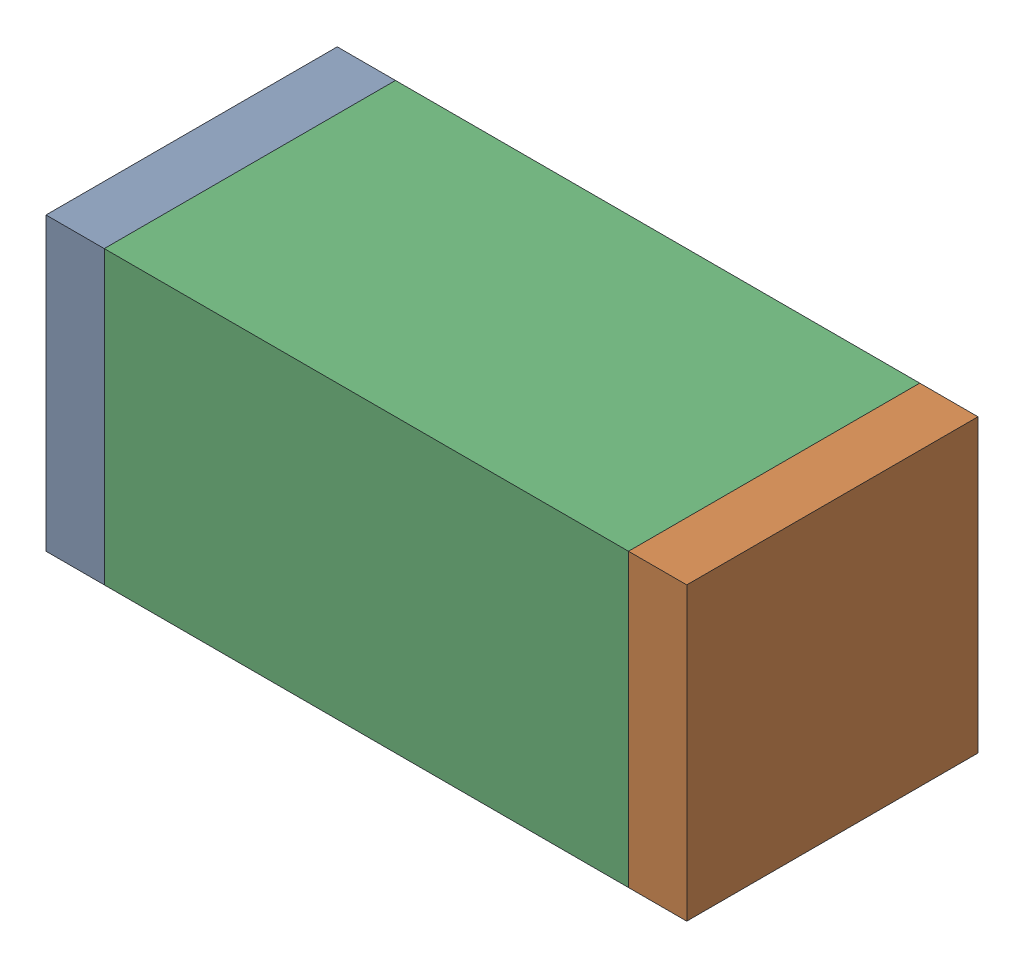
SolidWorks assembly C79, configuration Default. Lengths in mm.
Overall size (1.1 0.5 0.5).
6 component instances, 2 part files, 0 mates.
Components (placement in the parent):
- 810156080-1: 810156080 [Default] at (121.85 60.95 0) size (0.1 0.5 0.5)
  - Extruded_5-1: Extruded_5 [Default] at origin size (0.1 0.5 0.5)
- 810156080-2: 810156080 [Default] at (122.85 60.95 0) size (0.1 0.5 0.5)
  - Extruded_5-1: Extruded_5 [Default] at origin size (0.1 0.5 0.5)
- 836749680-1: 836749680 [Default] at (122.35 60.95 0) size (0.9 0.5 0.5)
  - Extruded_4-1: Extruded_4 [Default] at origin size (0.9 0.5 0.5)
